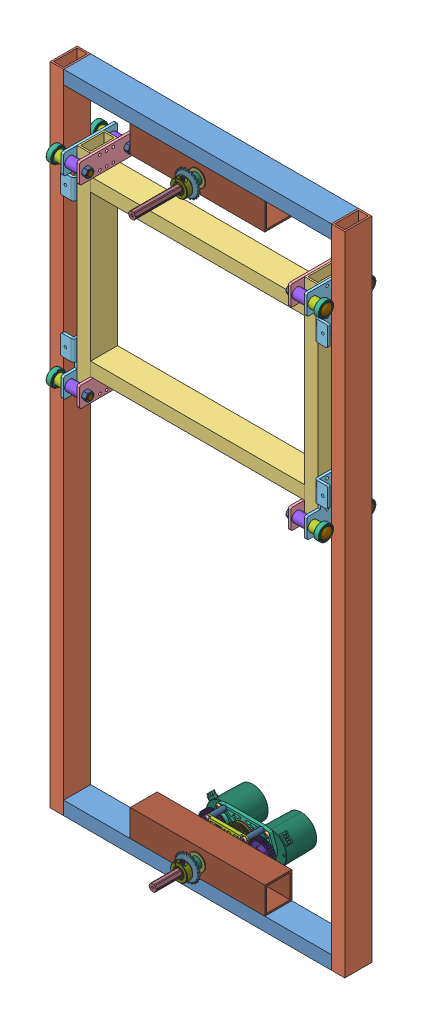
SolidWorks assembly Custom Brand New Solidwrks Assembly, configuration Default. Lengths in mm.
Overall size (862.57 1358.12 740.13).
120 component instances, 37 part files, 54 mates.
Components (placement in the parent):
- 19 and 7 8 in extrusion-1: 19 and 7 8 in extrusion [Default] at (683.3623 192.7403 428.5412) x (-1 0 0) z (0 1 0) size (504.82 50.8 25.4)
- 2 by 1 extrusion template-1: 2 by 1 extrusion template [Default] at (153.1373 167.3403 479.3412) size (25.4 1219.2 50.8)
- 2 by 1 extrusion template-2: 2 by 1 extrusion template [Default] at (683.3623 167.3403 479.3412) size (25.4 1219.2 50.8)
- 19 and 7 8 in extrusion-2: 19 and 7 8 in extrusion [Default] at (178.5373 1361.1403 428.5412) x (1 0 0) z (0 -1 0) size (504.82 50.8 25.4)
- carrige assembly-1: carrige assembly [Default] at (190.0122 1142.6943 245.5718) x (0.837169 0.457885 -0.299148) z (0.546944 -0.700852 0.457885) size (656.01 311.13 618.97)
  - 15 7 8 height-1: 15 7 8 height [Default] at (347.2127 190.7533 277.6779) x (-0.299148 0.837169 0.457885) z (-0.457885 -0.546944 0.700852) size (50.8 403.23 25.4)
  - 15 7 8 height-2: 15 7 8 height [Default] at (397.5525 225.4843 247.0662) x (-0.299148 0.837169 0.457885) z (0.837169 0 0.546944) size (50.8 403.23 25.4)
  - 15 7 8 height-3: 15 7 8 height [Default] at (38.7209 225.4843 12.6323) x (-0.299148 0.837169 0.457885) z (0.837169 0 0.546944) size (50.8 403.23 25.4)
  - 15 7 8 height-4: 15 7 8 height [Default] at (-116.834 39.6737 250.7293) x (-0.299148 0.837169 0.457885) z (0.457885 0.546944 -0.700852) size (50.8 403.23 25.4)
  - Roller-2: Roller [Défaut] at (218.0312 36.6261 530.5498) x (-0.299148 0.837169 0.457885) z (0.457885 0.546944 -0.700852) size (108.2 74.88 88.9)
    - am3793a-1: am3793a [Défaut] at (0 -30.16 0) size (101.6 4.76 38.1)
    - am3794a-1: am3794a [Défaut] at origin size (101.6 25 88.9)
    - am-0209b-1: am-0209b [Défaut] at (-39.8145 20.6375 0) x (1 0 0) z (0 1 0) size (28.57 28.57 9.53)
    - am1451-1: am1451 [Défaut] at (-39.8145 7.9375 0) x (0 0 1) z (-1 0 0) size (19.05 15.88 19.05)
    - am1451-2: am1451 [Défaut] at (39.8145 7.9375 0) x (-1 0 0) z (0 0 -1) size (19.05 15.88 19.05)
    - am-0209b-3: am-0209b [Défaut] at (39.8145 20.6375 0) x (1 0 0) z (0 1 0) size (28.57 28.57 9.53)
    - am1450-1: am1450 [Défaut] at (-39.8145 -17.46 0) size (19.05 25.4 19.05)
    - am1450-2: am1450 [Défaut] at (39.8145 -17.46 0) size (19.05 25.4 19.05)
    - round head bolt_ai-2: round head bolt_ai [RHBOLT 0.375-16x2.75x1-C] at (-39.8145 30.4292 0) x (0 -1 0) z (-1 0 0) size (74.88 20.65 20.65)
    - round head bolt_ai-3: round head bolt_ai [RHBOLT 0.375-16x2.75x1-C] at (39.8145 30.4292 0) x (0 -1 0) z (-1 0 0) size (74.88 20.65 20.65)
    - hex nut_ai-1: hex nut_ai [HNUT 0.3750-16-D-N] at (39.8145 -43.4798 0) x (0 0 1) z (0 -1 0) size (14.27 16.48 8.56)
    - hex nut_ai-2: hex nut_ai [HNUT 0.3750-16-D-N] at (-39.8145 -43.4798 0) x (0 0 1) z (0 -1 0) size (14.27 16.48 8.56)
  - Roller-3: Roller [Défaut] at (-170.0343 36.6261 277.0166) x (0.299148 -0.837169 -0.457885) z (0.457885 0.546944 -0.700852) size (108.2 74.88 88.9)
    - am3793a-1: am3793a [Défaut] at (0 -30.16 0) size (101.6 4.76 38.1)
    - am3794a-1: am3794a [Défaut] at origin size (101.6 25 88.9)
    - am-0209b-1: am-0209b [Défaut] at (-39.8145 20.6375 0) x (1 0 0) z (0 1 0) size (28.57 28.57 9.53)
    - am1451-1: am1451 [Défaut] at (-39.8145 7.9375 0) x (0 0 1) z (-1 0 0) size (19.05 15.88 19.05)
    - am1451-2: am1451 [Défaut] at (39.8145 7.9375 0) x (-1 0 0) z (0 0 -1) size (19.05 15.88 19.05)
    - am-0209b-3: am-0209b [Défaut] at (39.8145 20.6375 0) x (1 0 0) z (0 1 0) size (28.57 28.57 9.53)
    - am1450-1: am1450 [Défaut] at (-39.8145 -17.46 0) size (19.05 25.4 19.05)
    - am1450-2: am1450 [Défaut] at (39.8145 -17.46 0) size (19.05 25.4 19.05)
    - round head bolt_ai-2: round head bolt_ai [RHBOLT 0.375-16x2.75x1-C] at (-39.8145 30.4292 0) x (0 -1 0) z (-1 0 0) size (74.88 20.65 20.65)
    - round head bolt_ai-3: round head bolt_ai [RHBOLT 0.375-16x2.75x1-C] at (39.8145 30.4292 0) x (0 -1 0) z (-1 0 0) size (74.88 20.65 20.65)
    - hex nut_ai-1: hex nut_ai [HNUT 0.3750-16-D-N] at (39.8145 -43.4798 0) x (0 0 1) z (0 -1 0) size (14.27 16.48 8.56)
    - hex nut_ai-2: hex nut_ai [HNUT 0.3750-16-D-N] at (-39.8145 -43.4798 0) x (0 0 1) z (0 -1 0) size (14.27 16.48 8.56)
  - Roller-4: Roller [Défaut] at (385.2164 236.3291 274.6512) x (0.299148 -0.837169 -0.457885) z (-0.457885 -0.546944 0.700852) size (108.2 74.88 88.9)
    - am3793a-1: am3793a [Défaut] at (0 -30.16 0) size (101.6 4.76 38.1)
    - am3794a-1: am3794a [Défaut] at origin size (101.6 25 88.9)
    - am-0209b-1: am-0209b [Défaut] at (-39.8145 20.6375 0) x (1 0 0) z (0 1 0) size (28.57 28.57 9.53)
    - am1451-1: am1451 [Défaut] at (-39.8145 7.9375 0) x (0 0 1) z (-1 0 0) size (19.05 15.88 19.05)
    - am1451-2: am1451 [Défaut] at (39.8145 7.9375 0) x (-1 0 0) z (0 0 -1) size (19.05 15.88 19.05)
    - am-0209b-3: am-0209b [Défaut] at (39.8145 20.6375 0) x (1 0 0) z (0 1 0) size (28.57 28.57 9.53)
    - am1450-1: am1450 [Défaut] at (-39.8145 -17.46 0) size (19.05 25.4 19.05)
    - am1450-2: am1450 [Défaut] at (39.8145 -17.46 0) size (19.05 25.4 19.05)
    - round head bolt_ai-2: round head bolt_ai [RHBOLT 0.375-16x2.75x1-C] at (-39.8145 30.4292 0) x (0 -1 0) z (-1 0 0) size (74.88 20.65 20.65)
    - round head bolt_ai-3: round head bolt_ai [RHBOLT 0.375-16x2.75x1-C] at (39.8145 30.4292 0) x (0 -1 0) z (-1 0 0) size (74.88 20.65 20.65)
    - hex nut_ai-1: hex nut_ai [HNUT 0.3750-16-D-N] at (39.8145 -43.4798 0) x (0 0 1) z (0 -1 0) size (14.27 16.48 8.56)
    - hex nut_ai-2: hex nut_ai [HNUT 0.3750-16-D-N] at (-39.8145 -43.4798 0) x (0 0 1) z (0 -1 0) size (14.27 16.48 8.56)
  - Roller-5: Roller [Défaut] at (-2.8492 236.3291 21.1179) x (-0.299148 0.837169 0.457885) z (-0.457885 -0.546944 0.700852) size (108.2 74.88 88.9)
    - am3793a-1: am3793a [Défaut] at (0 -30.16 0) size (101.6 4.76 38.1)
    - am3794a-1: am3794a [Défaut] at origin size (101.6 25 88.9)
    - am-0209b-1: am-0209b [Défaut] at (-39.8145 20.6375 0) x (1 0 0) z (0 1 0) size (28.57 28.57 9.53)
    - am1451-1: am1451 [Défaut] at (-39.8145 7.9375 0) x (0 0 1) z (-1 0 0) size (19.05 15.88 19.05)
    - am1451-2: am1451 [Défaut] at (39.8145 7.9375 0) x (-1 0 0) z (0 0 -1) size (19.05 15.88 19.05)
    - am-0209b-3: am-0209b [Défaut] at (39.8145 20.6375 0) x (1 0 0) z (0 1 0) size (28.57 28.57 9.53)
    - am1450-1: am1450 [Défaut] at (-39.8145 -17.46 0) size (19.05 25.4 19.05)
    - am1450-2: am1450 [Défaut] at (39.8145 -17.46 0) size (19.05 25.4 19.05)
    - round head bolt_ai-2: round head bolt_ai [RHBOLT 0.375-16x2.75x1-C] at (-39.8145 30.4292 0) x (0 -1 0) z (-1 0 0) size (74.88 20.65 20.65)
    - round head bolt_ai-3: round head bolt_ai [RHBOLT 0.375-16x2.75x1-C] at (39.8145 30.4292 0) x (0 -1 0) z (-1 0 0) size (74.88 20.65 20.65)
    - hex nut_ai-1: hex nut_ai [HNUT 0.3750-16-D-N] at (39.8145 -43.4798 0) x (0 0 1) z (0 -1 0) size (14.27 16.48 8.56)
    - hex nut_ai-2: hex nut_ai [HNUT 0.3750-16-D-N] at (-39.8145 -43.4798 0) x (0 0 1) z (0 -1 0) size (14.27 16.48 8.56)
- REV-21-2099 1-to-1-1: REV-21-2099 1-to-1 [Default] at (430.9382 218.1403 387.2662) x (0 0 1) z (-1 0 0) size (99.54 69.01 161.62)
  - REV-21-2099 1-to-1.STEP-1: REV-21-2099 1-to-1.STEP [Default] at origin size (99.54 69.01 161.62)
    - REV-21-1879_For Motor Shaft, One Clip (Spaced 0.150).STEP-1: REV-21-1879_For Motor Shaft, One Clip (Spaced 0.150).STEP [Default] at (3.5 0 45.72) x (0 0 -1) z (1 0 0) size (13 13.75 24.57)
      - REV-21-1879.STEP-1: REV-21-1879.STEP [Default] at origin size (12.7 13.75 20)
      - Key_2mm_20mmLong.STEP-1: Key_2mm_20mmLong.STEP [Default] at (0.0325 4.05 10) x (0 0 -1) z (0 1 0) size (20 2 2)
      - Retaining_Ring_8mm.STEP-1: Retaining_Ring_8mm.STEP [Default] at (0 0 24.185) x (-1 0 0) z (0 0 1) size (13 13 0.76)
    - REV-21-1879_For Motor Shaft, One Clip (Spaced 0.150).STEP-2: REV-21-1879_For Motor Shaft, One Clip (Spaced 0.150).STEP [Default] at (3.5 0 -45.72) x (0 -1 0) z (1 0 0) size (13 13.75 24.57)
      - REV-21-1879.STEP-1: REV-21-1879.STEP [Default] at origin size (12.7 13.75 20)
      - Key_2mm_20mmLong.STEP-1: Key_2mm_20mmLong.STEP [Default] at (0.0325 4.05 10) x (0 0 -1) z (0 1 0) size (20 2 2)
      - Retaining_Ring_8mm.STEP-1: Retaining_Ring_8mm.STEP [Default] at (0 0 24.185) x (-1 0 0) z (0 0 1) size (13 13 0.76)
    - REV-21-2079.STEP-1: REV-21-2079.STEP [Default] at (20.6375 0 0) size (41.27 34.92 32.55)
    - REV-21-1650.STEP-1: REV-21-1650.STEP [Default] at (0 0 -45.72) x (0 -1 0) z (1 0 0) size (65.4 64.76 93.26)
    - REV-21-1650.STEP-2: REV-21-1650.STEP [Default] at (0 0 45.72) x (0 0 -1) z (1 0 0) size (65.4 64.76 93.26)
    - REV-21-3012.STEP-1: REV-21-3012.STEP [Default] at (17.375 0 0) x (0 1 0) z (1 0 0) size (48.1 48.1 12.7)
    - REV-21-1929.STEP-1: REV-21-1929.STEP [Default] at (17.7875 0 45.72) x (0 0 1) z (-1 0 0) size (48.2 48.2 12.7)
    - REV-21-1929.STEP-2: REV-21-1929.STEP [Default] at (17.7875 0 -45.72) x (0 -0.5 0.866025) z (-1 0 0) size (48.2 48.2 12.7)
    - REV-21-2541.STEP-1: REV-21-2541.STEP [Default] at (9.4375 0 0) x (0 0 -1) z (1 0 0) size (38.1 38.1 3.17)
    - REV-21-2541.STEP-2: REV-21-2541.STEP [Default] at (25.4875 0 0) x (0 0 -1) z (1 0 0) size (38.1 38.1 3.17)
    - REV-21-2542.STEP-1: REV-21-2542.STEP [Default] at (30.25 0 0) x (0 0 1) z (-1 0 0) size (38.1 38.1 6.35)
    - F6806ZZ.STEP-1: F6806ZZ.STEP [Default] at (4.35 0 0) x (0 -0.419542 0.907736) z (-1 0 0) size (45 45 7)
    - F6806ZZ.STEP-2: F6806ZZ.STEP [Default] at (36.925 0 0) x (0 -0.734429 0.678686) z (1 0 0) size (45 45 7)
    - #10 Button Head Cap Screws_0.500 Long.STEP-1: #10 Button Head Cap Screws_0.500 Long.STEP [Default] at (1.2827 25.4 45.72) x (0 0.07794 -0.996958) z (1 0 0) size (9.17 9.17 15.27)
    - #10 Button Head Cap Screws_0.500 Long.STEP-2: #10 Button Head Cap Screws_0.500 Long.STEP [Default] at (1.2827 -25.4 45.72) x (0 0.235024 -0.971989) z (1 0 0) size (9.17 9.17 15.27)
    - #10 Button Head Cap Screws_0.500 Long.STEP-3: #10 Button Head Cap Screws_0.500 Long.STEP [Default] at (1.2827 25.4 -45.72) x (0 0.356877 -0.934151) z (1 0 0) size (9.17 9.17 15.27)
    - #10 Button Head Cap Screws_0.500 Long.STEP-4: #10 Button Head Cap Screws_0.500 Long.STEP [Default] at (1.2827 -25.4 -45.72) x (0 0.442397 -0.896819) z (1 0 0) size (9.17 9.17 15.27)
    - #10 Button Head Cap Screws_1.500 Long.STEP-1: #10 Button Head Cap Screws_1.500 Long.STEP [Default] at (20.3327 27.454 35.2002) x (0 -0.07794 0.996958) z (1 0 0) size (9.17 9.17 40.67)
    - #10 Button Head Cap Screws_1.500 Long.STEP-2: #10 Button Head Cap Screws_1.500 Long.STEP [Default] at (20.3327 27.454 -35.2002) x (0 -0.235024 0.971989) z (1 0 0) size (9.17 9.17 40.67)
    - #10 Button Head Cap Screws_1.500 Long.STEP-3: #10 Button Head Cap Screws_1.500 Long.STEP [Default] at (20.3327 -27.454 -35.2002) x (0 -0.356877 0.934151) z (1 0 0) size (9.17 9.17 40.67)
    - #10 Button Head Cap Screws_1.500 Long.STEP-4: #10 Button Head Cap Screws_1.500 Long.STEP [Default] at (20.3327 -27.454 35.2002) x (0 -0.442397 0.896819) z (1 0 0) size (9.17 9.17 40.67)
    - REV-21-2078.STEP-1: REV-21-2078.STEP [Default] at (25.725 0 45.72) x (0 0 1) z (-1 0 0) size (14.29 14.29 3.17)
    - REV-21-2078.STEP-2: REV-21-2078.STEP [Default] at (25.725 0 -45.72) x (0 1 0) z (-1 0 0) size (14.29 14.29 3.17)
    - REV-21-2099-P01.STEP-1: REV-21-2099-P01.STEP [Default] at origin size (6.35 64.43 118.43)
    - REV-21-2099-P02.STEP-1: REV-21-2099-P02.STEP [Default] at (34.925 0 0) size (6.35 64.43 79.93)
    - REV-21-2005.STEP-1: REV-21-2005.STEP [Default] at (6.675 0 45.72) x (0 0 -1) z (1 0 0) size (18.29 18.29 6.35)
    - REV-21-2003.STEP-1: REV-21-2003.STEP [Default] at (10.6438 0 45.72) x (0 0 -1) z (1 0 0) size (18.29 18.29 1.59)
    - REV-21-2003.STEP-2: REV-21-2003.STEP [Default] at (10.6438 0 -45.72) x (0 0 -1) z (1 0 0) size (18.29 18.29 1.59)
    - REV-21-2005.STEP-2: REV-21-2005.STEP [Default] at (6.675 0 -45.72) x (0 0 -1) z (1 0 0) size (18.29 18.29 6.35)
    - #10 Unthreaded Spacers_1.125in Long.STEP-1: #10 Unthreaded Spacers_1.125in Long.STEP [Default] at (20.6375 27.454 35.2002) size (28.57 9.53 9.53)
    - #10 Unthreaded Spacers_1.125in Long.STEP-2: #10 Unthreaded Spacers_1.125in Long.STEP [Default] at (20.6375 -27.454 35.2002) size (28.57 9.53 9.53)
    - #10 Unthreaded Spacers_1.125in Long.STEP-3: #10 Unthreaded Spacers_1.125in Long.STEP [Default] at (20.6375 27.454 -35.2002) size (28.57 9.53 9.53)
    - #10 Unthreaded Spacers_1.125in Long.STEP-4: #10 Unthreaded Spacers_1.125in Long.STEP [Default] at (20.6375 -27.454 -35.2002) size (28.57 9.53 9.53)
- Elevator Attachment-1: Elevator Attachment [Default] at (303.9498 243.5403 479.3412) x (1 0 0) z (0 1 0) size (254 50.8 50.8)
- Half inch flange bearing.step-1: Half inch flange bearing.step [Default] at (430.9498 218.1403 434.9445) x (-0.999907 -0.013661 0) z (0 0 -1) size (31.12 31.12 7.93)
- Half inch flange bearing.step-2: Half inch flange bearing.step [Default] at (430.9498 218.1403 472.9378) size (31.12 31.12 7.93)
- REV-half inch Hex Shaft 6.92 in-1: REV-half inch Hex Shaft 6.92 in [Default] at (430.9411 218.1453 845.3162) x (0.866025 -0.5 0) z (0 0 1) size (12.69 13.74 175.77)
- WCP-0560 Rev1.step-1: WCP-0560 Rev1.step [Default] at (430.9587 218.1149 498.3277) x (0.866025 0.5 0) z (0 0 1) size (47.96 47.68 9.53)
- WCP-0790_500L_500_hex.step-1: WCP-0790_500L_500_hex.step [Default] at (430.8649 218.0133 487.2152) x (-1 0 0) z (0 0 -1) size (19.5 19.5 12.7)
- Elevator Attachment-3: Elevator Attachment [Default] at (303.9498 1310.3403 479.3412) size (254 50.8 50.8)
- Half inch flange bearing.step-3: Half inch flange bearing.step [Default] at (430.9498 1335.7403 434.9445) x (-1 0 0) z (0 0 -1) size (31.12 31.12 7.93)
- Half inch flange bearing.step-4: Half inch flange bearing.step [Default] at (430.9498 1335.7403 472.9378) x (0.540386 0.841418 0) z (0 0 1) size (31.12 31.12 7.93)
- WCP-0560 Rev1.step-2: WCP-0560 Rev1.step [Default] at (430.9601 1335.7094 498.3277) x (-0.047279 -0.998882 0) z (0 0 1) size (47.96 47.68 9.53)
- REV-half inch Hex Shaft 6.92 in-2: REV-half inch Hex Shaft 6.92 in [Default] at (430.944 1335.7406 145.5852) x (-0.047279 -0.998882 0) z (0 0 -1) size (12.69 13.74 175.77)
- WCP-0790_500L_500_hex.step-2: WCP-0790_500L_500_hex.step [Default] at (431.0139 1335.6051 487.2152) x (-0.998882 0.047279 0) z (0 0 -1) size (19.5 19.5 12.7)
- am-1526 500Hex HD Collar Clamp.STEP-1: am-1526 500Hex HD Collar Clamp.STEP [Default] at (370.6257 292.0106 548.8001) x (-0.5 0.866025 0) z (0 0 -1) size (31.73 31.75 12.7)
  - am-1238a 500Hex Collar Clamp Body.STEP-1: am-1238a 500Hex Collar Clamp Body.STEP [Default] at (-94.2794 15.3021 33.01) size (31.73 31.75 12.7)
  - 10-32x0500_shcs_HX-SHCS 0.19-32x1.375x1-C.STEP-1: 10-32x0500_shcs_HX-SHCS 0.19-32x1.375x1-C.STEP [Default] at (-83.1669 24.154 39.36) x (0 -1 0) z (0 0 1) size (17.53 7.94 7.94)
- am-1526 500Hex HD Collar Clamp.STEP-2: am-1526 500Hex HD Collar Clamp.STEP [Default] at (374.1883 1412.3749 548.8001) x (-0.458496 0.888696 0) z (0 0 -1) size (31.73 31.75 12.7)
  - am-1238a 500Hex Collar Clamp Body.STEP-1: am-1238a 500Hex Collar Clamp Body.STEP [Default] at (-94.2794 15.3021 33.01) size (31.73 31.75 12.7)
  - 10-32x0500_shcs_HX-SHCS 0.19-32x1.375x1-C.STEP-1: 10-32x0500_shcs_HX-SHCS 0.19-32x1.375x1-C.STEP [Default] at (-83.1669 24.154 39.36) x (0 -1 0) z (0 0 1) size (17.53 7.94 7.94)
Mates (geometry in assembly coordinates):
- Coincident2: coincident aligned: plane of 19 and 7 8 in extrusion-1 through (178.5373 192.7403 479.3412) normal (0 0 1); plane of 2 by 1 extrusion template-2 through (683.3623 1386.5403 479.3412) normal (0 0 1)
- Coincident3: coincident aligned: plane of 19 and 7 8 in extrusion-1 through (178.5373 167.3403 428.5412) normal (0 -1 0); plane of 2 by 1 extrusion template-2 through (683.3623 167.3403 479.3412) normal (0 -1 0)
- Coincident4: coincident anti-aligned: plane of 19 and 7 8 in extrusion-1 through (683.3623 192.7403 428.5412) normal (1 0 0); plane of 2 by 1 extrusion template-2 through (683.3623 1386.5403 479.3412) normal (-1 0 0)
- Coincident5: coincident: plane of 19 and 7 8 in extrusion-1 through (178.5373 192.7403 479.3412) normal (0 0 1); plane of 2 by 1 extrusion template-1 through (153.1373 1386.5403 479.3412) normal (0 0 1)
- Coincident6: coincident: plane of 19 and 7 8 in extrusion-1 through (178.5373 167.3403 428.5412) normal (0 -1 0); plane of 2 by 1 extrusion template-1 through (153.1373 167.3403 479.3412) normal (0 -1 0)
- Coincident7: coincident anti-aligned: plane of 19 and 7 8 in extrusion-1 through (178.5373 192.7403 428.5412) normal (-1 0 0); plane of 2 by 1 extrusion template-1 through (178.5373 1386.5403 479.3412) normal (1 0 0)
- Coincident8: coincident anti-aligned: plane of 2 by 1 extrusion template-1 through (178.5373 1386.5403 479.3412) normal (1 0 0); plane of 19 and 7 8 in extrusion-2 through (178.5373 1361.1403 428.5412) normal (-1 0 0)
- Coincident9: coincident aligned: plane of 2 by 1 extrusion template-1 through (153.1373 1386.5403 428.5412) normal (0 0 -1); plane of 19 and 7 8 in extrusion-2 through (683.3623 1361.1403 428.5412) normal (0 0 -1)
- Coincident10: coincident aligned: plane of 2 by 1 extrusion template-2 through (683.3623 1386.5403 479.3412) normal (0 1 0); plane of 19 and 7 8 in extrusion-2 through (683.3623 1386.5403 428.5412) normal (0 1 0)
- Coincident12: coincident aligned: plane of 2 by 1 extrusion template-2 through (683.3623 1386.5403 428.5412) normal (0 0 -1); plane of carrige assembly-1/15 7 8 height-2 through (657.9623 871.673 428.5412) normal (0 0 -1)
- Width1: width aligned: plane of 2 by 1 extrusion template-2 through (683.3623 1386.5403 428.5412) normal (0 0 -1); plane of 2 by 1 extrusion template-1 through (153.1373 1386.5403 428.5412) normal (0 0 -1); plane of carrige assembly-1/15 7 8 height-2 through (657.9623 871.673 428.5412) normal (0 0 -1); plane of carrige assembly-1/15 7 8 height-3 through (229.3373 871.673 428.5412) normal (0 0 -1)
- Width2: width anti-aligned: plane of 2 by 1 extrusion template-2 through (683.3623 1386.5403 479.3412) normal (-1 0 0); plane of 2 by 1 extrusion template-1 through (178.5373 1386.5403 479.3412) normal (1 0 0); plane of carrige assembly-1/15 7 8 height-2 through (657.9623 871.673 428.5412) normal (1 0 0); plane of carrige assembly-1/15 7 8 height-3 through (203.9373 871.673 428.5412) normal (-1 0 0)
- Coincident13: coincident anti-aligned: plane of 19 and 7 8 in extrusion-1 through (178.5373 192.7403 428.5412) normal (0 1 0); plane of Elevator Attachment-1 through (557.9498 192.7403 479.3412) normal (0 -1 0)
- Coincident14: coincident aligned: plane of 19 and 7 8 in extrusion-1 through (178.5373 192.7403 428.5412) normal (0 0 -1); plane of Elevator Attachment-1 through (557.9498 243.5403 428.5412) normal (0 0 -1)
- Width3: width aligned: plane of 2 by 1 extrusion template-1 through (178.5373 1386.5403 479.3412) normal (1 0 0); plane of 2 by 1 extrusion template-2 through (683.3623 1386.5403 479.3412) normal (-1 0 0); plane of Elevator Attachment-1 through (557.9498 243.5403 479.3412) normal (1 0 0); plane of Elevator Attachment-1 through (303.9498 243.5403 479.3412) normal (-1 0 0)
- Coincident16: coincident anti-aligned: plane of Elevator Attachment-1 through (557.9498 243.5403 428.5412) normal (0 0 -1); plane of Half inch flange bearing.step-1 through (416.9811 217.9495 428.5412) normal (0 0 1)
- Concentric2: concentric aligned: cylinder of Elevator Attachment-1 through (430.9498 218.1403 83.8784) axis (0 0 1) radius 12.7; cylinder of Half inch flange bearing.step-1 through (430.9498 218.1403 427.0172) axis (0 0 1) radius 14.2875
- Concentric3: concentric anti-aligned: cylinder of Elevator Attachment-1 through (430.9498 218.1403 83.8784) axis (0 0 1) radius 12.7; cylinder of Half inch flange bearing.step-2 through (430.9498 218.1403 480.8652) axis (0 0 -1) radius 14.2875
- Coincident17: coincident anti-aligned: plane of Elevator Attachment-1 through (557.9498 243.5403 479.3412) normal (0 0 1); plane of Half inch flange bearing.step-2 through (444.9198 218.1403 479.3412) normal (0 0 -1)
- Coincident18: coincident anti-aligned: plane of REV-21-2099 1-to-1-1/REV-21-2099 1-to-1.STEP-1/REV-21-2099-P02.STEP-1 through (430.9382 218.1403 428.5412) normal (0 0 1); plane of Elevator Attachment-1 through (557.9498 243.5403 428.5412) normal (0 0 -1)
- Coincident19: coincident aligned: plane of REV-21-2099 1-to-1-1/REV-21-2099 1-to-1.STEP-1/REV-21-2079.STEP-1 through (425.8885 224.5613 388.1162) normal (0 0 -1); plane of REV-half inch Hex Shaft 6.92 in-1 through (430.9411 218.1453 388.1162) normal (0 0 -1)
- Coincident20: coincident anti-aligned: plane of REV-21-2099 1-to-1-1/REV-21-2099 1-to-1.STEP-1/REV-21-2079.STEP-1 through (438.2706 218.1403 387.2662) normal (-0.866025 -0.5 0); plane of REV-half inch Hex Shaft 6.92 in-1 through (436.4361 221.3178 1302.5162) normal (0.866025 0.5 0)
- Coincident21: coincident anti-aligned: plane of REV-21-2099 1-to-1-1/REV-21-2099 1-to-1.STEP-1/REV-21-2079.STEP-1 through (434.6044 224.4903 387.2662) normal (0 -1 0); plane of REV-half inch Hex Shaft 6.92 in-1 through (430.9411 224.4903 1302.5162) normal (0 1 0)
- Coincident23: coincident anti-aligned: plane of Half inch flange bearing.step-2 through (427.2836 224.4903 480.8652) normal (0 -1 0); plane of REV-half inch Hex Shaft 6.92 in-1 through (430.9411 224.4903 1302.5162) normal (0 1 0)
- Coincident24: coincident anti-aligned: plane of Half inch flange bearing.step-2 through (427.2836 211.7903 480.8652) normal (0.866025 0.5 0); plane of REV-half inch Hex Shaft 6.92 in-1 through (425.4462 214.9728 1302.5162) normal (-0.866025 -0.5 0)
- Parallel1: parallel aligned: plane of 19 and 7 8 in extrusion-1 through (178.5373 167.3403 428.5412) normal (0 -1 0); plane of REV-21-2099 1-to-1-1/REV-21-2099 1-to-1.STEP-1/REV-21-2099-P02.STEP-1 through (430.9382 185.9238 428.5412) normal (0 -1 0)
- Coincident42: coincident anti-aligned: plane of REV-half inch Hex Shaft 6.92 in-1 through (430.9411 224.4903 1302.5162) normal (0 1 0); plane of WCP-0790_500L_500_hex.step-1 through (427.1254 224.4903 480.8652) normal (0 -1 0)
- Coincident43: coincident anti-aligned: plane of REV-half inch Hex Shaft 6.92 in-1 through (436.4361 221.3178 1302.5162) normal (0.866025 0.5 0); plane of WCP-0790_500L_500_hex.step-1 through (434.6044 224.4903 480.8652) normal (-0.866025 -0.5 0)
- Coincident44: coincident anti-aligned: plane of Half inch flange bearing.step-2 through (446.5073 218.1403 480.8652) normal (0 0 1); plane of WCP-0790_500L_500_hex.step-1 through (430.8649 218.0133 480.8652) normal (0 0 -1)
- Coincident45: coincident anti-aligned: plane of REV-half inch Hex Shaft 6.92 in-1 through (425.4462 221.3178 1302.5162) normal (-0.866025 0.5 0); plane of WCP-0560 Rev1.step-1 through (427.2778 224.4903 493.5652) normal (0.866025 -0.5 0)
- Coincident46: coincident anti-aligned: plane of REV-half inch Hex Shaft 6.92 in-1 through (430.9411 224.4903 1302.5162) normal (0 1 0); plane of WCP-0560 Rev1.step-1 through (434.6395 224.4903 493.5652) normal (0 -1 0)
- Coincident47: coincident anti-aligned: plane of WCP-0560 Rev1.step-1 through (430.9587 218.1149 493.5652) normal (0 0 -1); plane of WCP-0790_500L_500_hex.step-1 through (430.8649 218.0133 493.5652) normal (0 0 1)
- Coincident48: coincident anti-aligned: plane of 19 and 7 8 in extrusion-2 through (683.3623 1361.1403 428.5412) normal (0 -1 0); plane of Elevator Attachment-3 through (557.9498 1361.1403 479.3412) normal (0 1 0)
- Coincident49: coincident aligned: plane of 19 and 7 8 in extrusion-2 through (683.3623 1361.1403 428.5412) normal (0 0 -1); plane of Elevator Attachment-3 through (557.9498 1310.3403 428.5412) normal (0 0 -1)
- Width6: width anti-aligned: plane of 2 by 1 extrusion template-1 through (178.5373 1386.5403 479.3412) normal (1 0 0); plane of 2 by 1 extrusion template-2 through (683.3623 1386.5403 479.3412) normal (-1 0 0); plane of Elevator Attachment-3 through (303.9498 1310.3403 479.3412) normal (-1 0 0); plane of Elevator Attachment-3 through (557.9498 1310.3403 479.3412) normal (1 0 0)
- Coincident50: coincident anti-aligned: plane of Elevator Attachment-3 through (557.9498 1310.3403 428.5412) normal (0 0 -1); plane of Half inch flange bearing.step-3 through (416.9798 1335.7403 428.5412) normal (0 0 1)
- Concentric4: concentric anti-aligned: cylinder of Elevator Attachment-3 through (430.9498 1335.7403 824.0039) axis (0 0 -1) radius 12.7; cylinder of Half inch flange bearing.step-3 through (430.9498 1335.7403 427.0172) axis (0 0 1) radius 14.2875
- Coincident51: coincident anti-aligned: plane of Elevator Attachment-3 through (557.9498 1310.3403 479.3412) normal (0 0 1); plane of Half inch flange bearing.step-4 through (438.499 1347.4949 479.3412) normal (0 0 -1)
- Concentric5: concentric aligned: cylinder of Elevator Attachment-3 through (430.9498 1335.7403 824.0039) axis (0 0 -1) radius 12.7; cylinder of Half inch flange bearing.step-4 through (430.9498 1335.7403 480.8652) axis (0 0 -1) radius 14.2875
- Distance1: distance = 0 mm aligned: plane of REV-half inch Hex Shaft 6.92 in-2 through (428.6501 1287.2759 427.0172) normal (0 0 -1); plane of Half inch flange bearing.step-3 through (415.3923 1335.7403 427.0172) normal (0 0 -1)
- Coincident53: coincident anti-aligned: plane of Half inch flange bearing.step-4 through (426.9875 1329.5708 480.8652) normal (0.888696 0.458496 0); plane of REV-half inch Hex Shaft 6.92 in-2 through (425.3052 1332.8314 -311.6148) normal (-0.888696 -0.458496 0)
- Coincident54: coincident anti-aligned: plane of Half inch flange bearing.step-4 through (423.6256 1336.087 480.8652) normal (0.841418 -0.540386 0); plane of REV-half inch Hex Shaft 6.92 in-2 through (425.6052 1339.1693 -311.6148) normal (-0.841418 0.540386 0)
- Coincident55: coincident anti-aligned: plane of Half inch flange bearing.step-4 through (439.3568 1348.8307 480.8652) normal (0 0 1); plane of WCP-0790_500L_500_hex.step-2 through (431.0139 1335.6051 480.8652) normal (0 0 -1)
- Coincident56: coincident anti-aligned: plane of REV-half inch Hex Shaft 6.92 in-2 through (431.244 1342.0785 -311.6148) normal (0.047279 0.998882 0); plane of WCP-0790_500L_500_hex.step-2 through (427.5848 1342.2517 480.8652) normal (-0.047279 -0.998882 0)
- Coincident57: coincident anti-aligned: plane of REV-half inch Hex Shaft 6.92 in-2 through (425.6052 1339.1693 -311.6148) normal (-0.841418 0.540386 0); plane of WCP-0790_500L_500_hex.step-2 through (423.5433 1335.9587 480.8652) normal (0.841418 -0.540386 0)
- Coincident58: coincident anti-aligned: plane of WCP-0560 Rev1.step-2 through (430.9601 1335.7094 493.5652) normal (0 0 -1); plane of WCP-0790_500L_500_hex.step-2 through (431.0139 1335.6051 493.5652) normal (0 0 1)
- Coincident59: coincident anti-aligned: plane of WCP-0560 Rev1.step-2 through (434.9383 1341.9036 493.5652) normal (-0.047279 -0.998882 0); plane of REV-half inch Hex Shaft 6.92 in-2 through (431.244 1342.0785 -311.6148) normal (0.047279 0.998882 0)
- Coincident60: coincident anti-aligned: plane of WCP-0560 Rev1.step-2 through (427.5848 1342.2517 493.5652) normal (0.841418 -0.540386 0); plane of REV-half inch Hex Shaft 6.92 in-2 through (425.6052 1339.1693 -311.6148) normal (-0.841418 0.540386 0)
- Coincident61: coincident anti-aligned: plane of WCP-0560 Rev1.step-1 through (430.9587 218.1149 503.0902) normal (0 0 1); plane of am-1526 500Hex HD Collar Clamp.STEP-1/am-1238a 500Hex Collar Clamp Body.STEP-1 through (431.0173 218.0133 503.0902) normal (0 0 -1)
- Coincident62: coincident anti-aligned: plane of REV-half inch Hex Shaft 6.92 in-1 through (430.9411 224.4903 1302.5162) normal (0 1 0); plane of am-1526 500Hex HD Collar Clamp.STEP-1/am-1238a 500Hex Collar Clamp Body.STEP-1 through (427.2778 224.4903 515.7902) normal (0 -1 0)
- Coincident63: coincident anti-aligned: plane of REV-half inch Hex Shaft 6.92 in-1 through (425.4462 221.3178 1302.5162) normal (-0.866025 0.5 0); plane of am-1526 500Hex HD Collar Clamp.STEP-1/am-1238a 500Hex Collar Clamp Body.STEP-1 through (423.5383 218.0133 515.7902) normal (0.866025 -0.5 0)
- Coincident64: coincident anti-aligned: plane of WCP-0560 Rev1.step-2 through (430.9601 1335.7094 503.0902) normal (0 0 1); plane of am-1526 500Hex HD Collar Clamp.STEP-2/am-1238a 500Hex Collar Clamp Body.STEP-1 through (431.0139 1335.6051 503.0902) normal (0 0 -1)
- Coincident65: coincident anti-aligned: plane of REV-half inch Hex Shaft 6.92 in-2 through (431.244 1342.0785 -311.6148) normal (0.047279 0.998882 0); plane of am-1526 500Hex HD Collar Clamp.STEP-2/am-1238a 500Hex Collar Clamp Body.STEP-1 through (427.5848 1342.2517 515.7902) normal (-0.047279 -0.998882 0)
- Coincident66: coincident anti-aligned: plane of REV-half inch Hex Shaft 6.92 in-2 through (425.6052 1339.1693 -311.6148) normal (-0.841418 0.540386 0); plane of am-1526 500Hex HD Collar Clamp.STEP-2/am-1238a 500Hex Collar Clamp Body.STEP-1 through (423.5433 1335.9587 515.7902) normal (0.841418 -0.540386 0)
